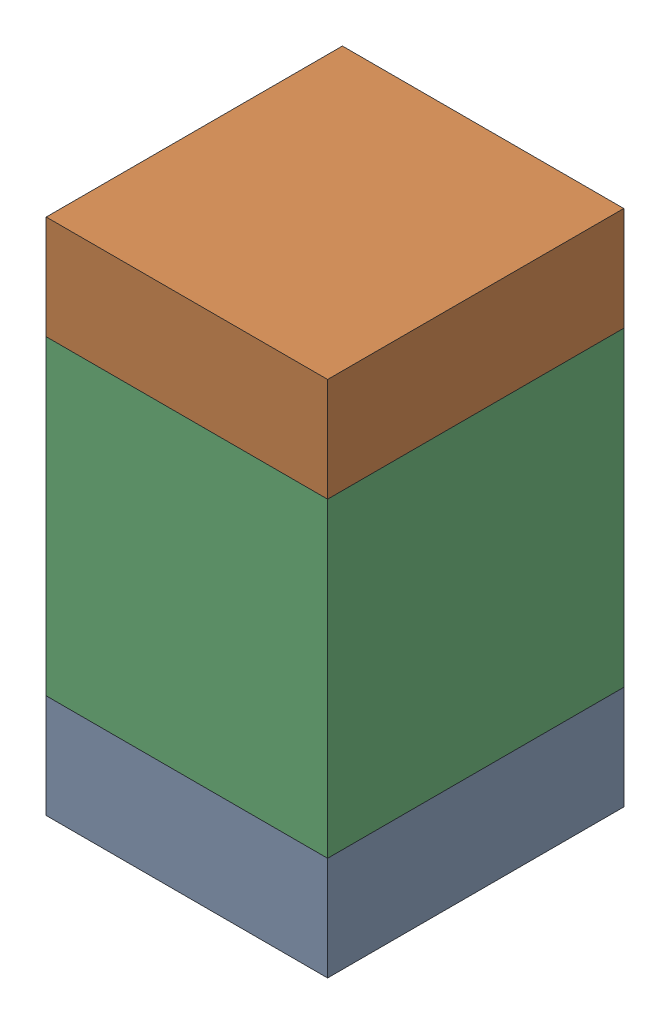
SolidWorks assembly C11-1, configuration Default. Lengths in mm.
Overall size (0.95 1.75 1).
6 component instances, 2 part files, 0 mates.
Components (placement in the parent):
- 959208664-1-1: 959208664-1 [Default] at (122.4827 75.652 0) size (0.95 0.35 1)
  - Extruded-45-1: Extruded-45 [Default] at origin size (0.95 0.35 1)
- 959208664-1-2: 959208664-1 [Default] at (122.4827 77.052 0) size (0.95 0.35 1)
  - Extruded-45-1: Extruded-45 [Default] at origin size (0.95 0.35 1)
- 959208528-1-1: 959208528-1 [Default] at (122.4827 76.352 0) size (0.95 1.05 1)
  - Extruded-46-1: Extruded-46 [Default] at origin size (0.95 1.05 1)
